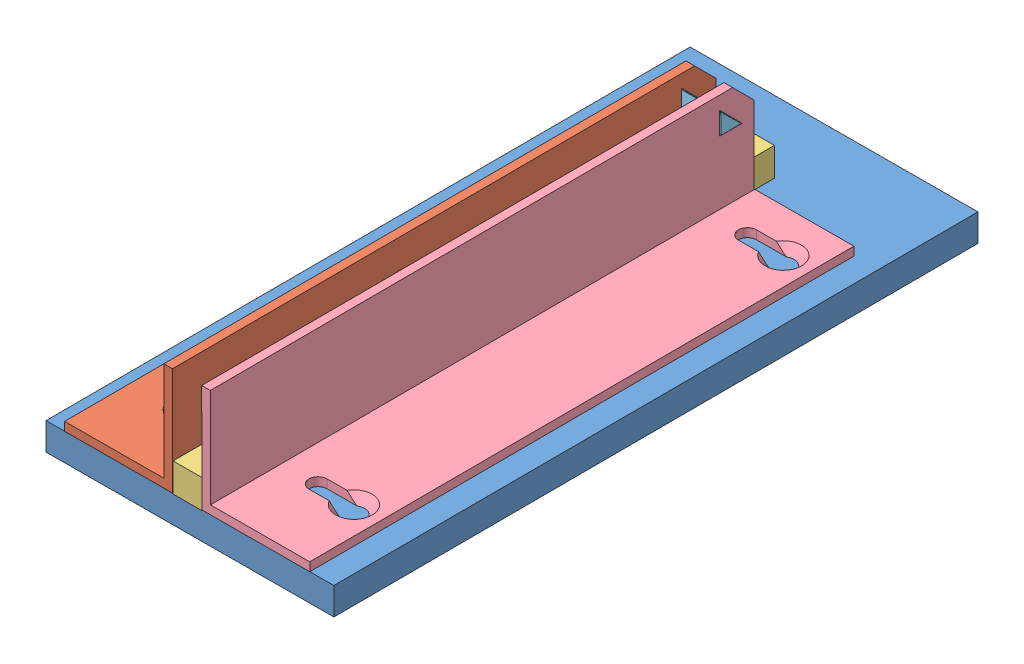
SolidWorks assembly CrystalSanding, configuration Default. Lengths in mm.
Overall size (102.25 48.24 229.15).
5 component instances, 5 part files, 0 mates.
Components (placement in the parent):
- AlBase^CrystalSanding-1: AlBase^CrystalSanding [Default] at (69.9159 53.1869 59.3671) x (-0.002775 -0.000435 -0.999996) z (-0.999995 -0.001212 0.002776) size (228.6 9.65 101.6) (virtual)
- AlAngle(1)^CrystalSanding-8: AlAngle(1)^CrystalSanding [Default] at (111.8205 53.5096 59.5421) x (-0.002775 -0.000435 -0.999996) z (0.999995 0.001212 -0.002776) size (193.13 38.1 38.1) (virtual)
- Crystal^CrystalSanding-1: Crystal^CrystalSanding [Default] at (114.9159 53.1694 59.396) x (-0.002775 -0.000435 -0.999996) z (0.001213 -0.999999 0.000432) size (203.2 10.16 10.16) (virtual)
- Copy of AlAngle(1)^CrystalSanding-3: Copy of AlAngle(1)^CrystalSanding [Default] at (127.6739 53.4252 -143.7109) x (0.002775 0.000511 0.999996) z (-0.999995 -0.001212 0.002775) size (193.13 38.1 38.1) (virtual)
- SandingPiece^CrystalSanding-1: SandingPiece^CrystalSanding [Default] at (127.9138 86.3517 -121.4363) x (0.002786 -0.008291 0.999962) z (-0.999995 -0.001212 0.002776) size (7.18 7.18 16.51) (virtual)
